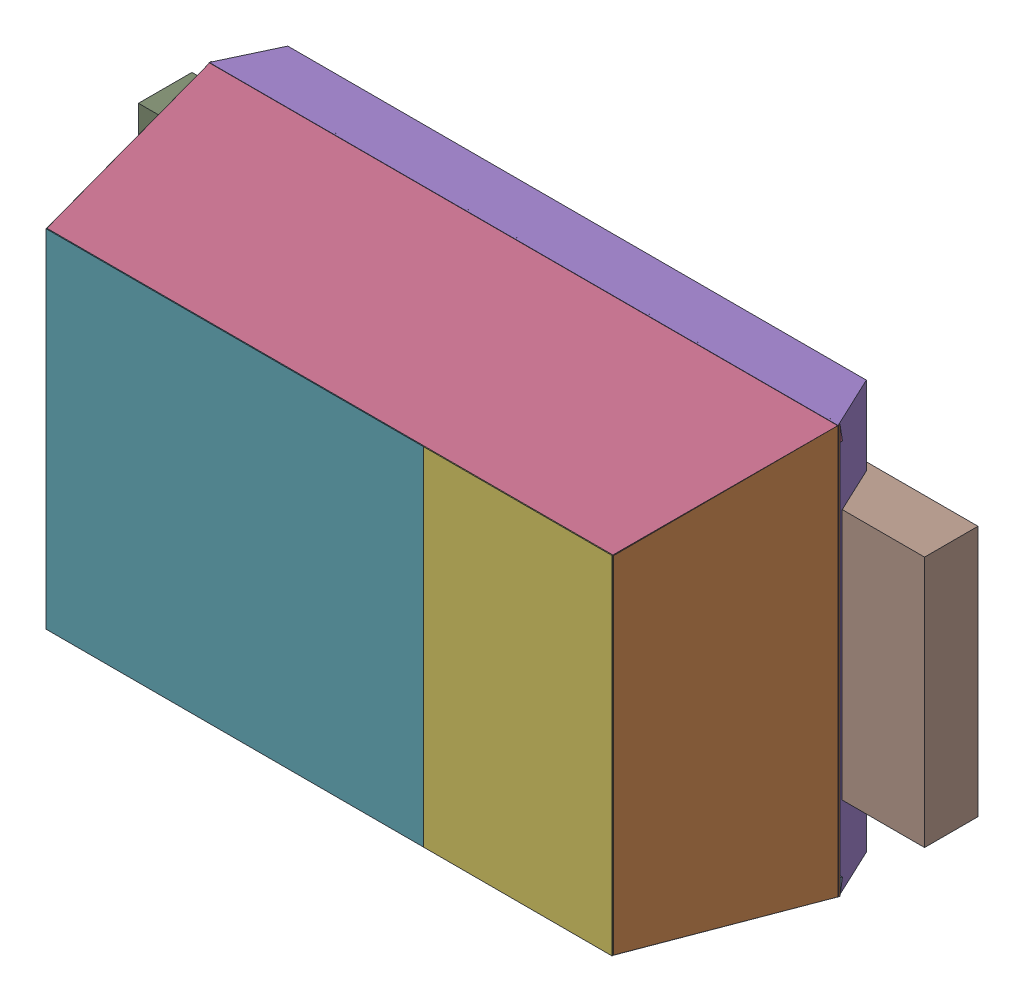
SolidWorks assembly User Library-Arduino Nano 3.0_User Library-TUMD2_Free-Models, configuration Default. Lengths in mm.
Overall size (2.5 1.3 0.81).
18 component instances, 7 part files, 0 mates.
Components (placement in the parent):
- User Library-Arduino Nano 3.0_User Library-TUMD2_BODY_L-1: User Library-Arduino Nano 3.0_User Library-TUMD2_BODY_L [Default] at (1.08 -0.6007 0.5) x (-1 0 0) z (0 0.987688 -0.156434) size (2 0.63 0.05)
  - User Library-Arduino Nano 3.0_User Library-TUMD2_Extruded-1: User Library-Arduino Nano 3.0_User Library-TUMD2_Extruded [Default] at origin size (2 0.63 0.05)
- User Library-Arduino Nano 3.0_User Library-TUMD2_BODY_S-1: User Library-Arduino Nano 3.0_User Library-TUMD2_BODY_S [Default] at (2.0307 0 0.5) x (0.156434 0 -0.987688) z (-0.987688 0 -0.156434) size (0.63 1.3 0.05)
  - User Library-Arduino Nano 3.0_User Library-TUMD2_Extruded_2-1: User Library-Arduino Nano 3.0_User Library-TUMD2_Extruded_2 [Default] at origin size (0.63 1.3 0.05)
- User Library-Arduino Nano 3.0_User Library-TUMD2_BODY_S-2: User Library-Arduino Nano 3.0_User Library-TUMD2_BODY_S [Default] at (0.1293 0 0.5) x (-0.156434 0 -0.987688) z (0.987688 0 -0.156434) size (0.63 1.3 0.05)
  - User Library-Arduino Nano 3.0_User Library-TUMD2_Extruded_2-1: User Library-Arduino Nano 3.0_User Library-TUMD2_Extruded_2 [Default] at origin size (0.63 1.3 0.05)
- User Library-Arduino Nano 3.0_User Library-TUMD2_BODY_L-2: User Library-Arduino Nano 3.0_User Library-TUMD2_BODY_L [Default] at (1.08 0.6007 0.5) x (1 0 0) z (0 -0.987688 -0.156434) size (2 0.63 0.05)
  - User Library-Arduino Nano 3.0_User Library-TUMD2_Extruded-1: User Library-Arduino Nano 3.0_User Library-TUMD2_Extruded [Default] at origin size (2 0.63 0.05)
- User Library-Arduino Nano 3.0_User Library-TUMD2_BASE-1: User Library-Arduino Nano 3.0_User Library-TUMD2_BASE [Default] at (1.08 0.65 0.11) x (1 0 0) z (0 -1 0) size (2 0.17 1.3)
  - User Library-Arduino Nano 3.0_User Library-TUMD2_Extruded_3-1: User Library-Arduino Nano 3.0_User Library-TUMD2_Extruded_3 [Default] at origin size (2 0.17 1.3)
- User Library-Arduino Nano 3.0_User Library-TUMD2_702825728-1: User Library-Arduino Nano 3.0_User Library-TUMD2_702825728 [Default] at (1.68 0 0.75) size (0.6 1.1 0.06)
  - User Library-Arduino Nano 3.0_User Library-TUMD2_Extruded_4-1: User Library-Arduino Nano 3.0_User Library-TUMD2_Extruded_4 [Default] at origin size (0.6 1.1 0.06)
- User Library-Arduino Nano 3.0_User Library-TUMD2_702828800-1: User Library-Arduino Nano 3.0_User Library-TUMD2_702828800 [Default] at (0.78 0 0.75) size (1.2 1.1 0.06)
  - User Library-Arduino Nano 3.0_User Library-TUMD2_Extruded_5-1: User Library-Arduino Nano 3.0_User Library-TUMD2_Extruded_5 [Default] at origin size (1.2 1.1 0.06)
- User Library-Arduino Nano 3.0_User Library-TUMD2_675155360-1: User Library-Arduino Nano 3.0_User Library-TUMD2_675155360 [Default] at (1.58 0 0) size (1.5 0.8 0.17)
  - User Library-Arduino Nano 3.0_User Library-TUMD2_Extruded_6-1: User Library-Arduino Nano 3.0_User Library-TUMD2_Extruded_6 [Default] at origin size (1.5 0.8 0.17)
- User Library-Arduino Nano 3.0_User Library-TUMD2_676056384-1: User Library-Arduino Nano 3.0_User Library-TUMD2_676056384 [Default] at (0.005 0 0) size (0.35 0.8 0.17)
  - User Library-Arduino Nano 3.0_User Library-TUMD2_Extruded_7-1: User Library-Arduino Nano 3.0_User Library-TUMD2_Extruded_7 [Default] at origin size (0.35 0.8 0.17)
